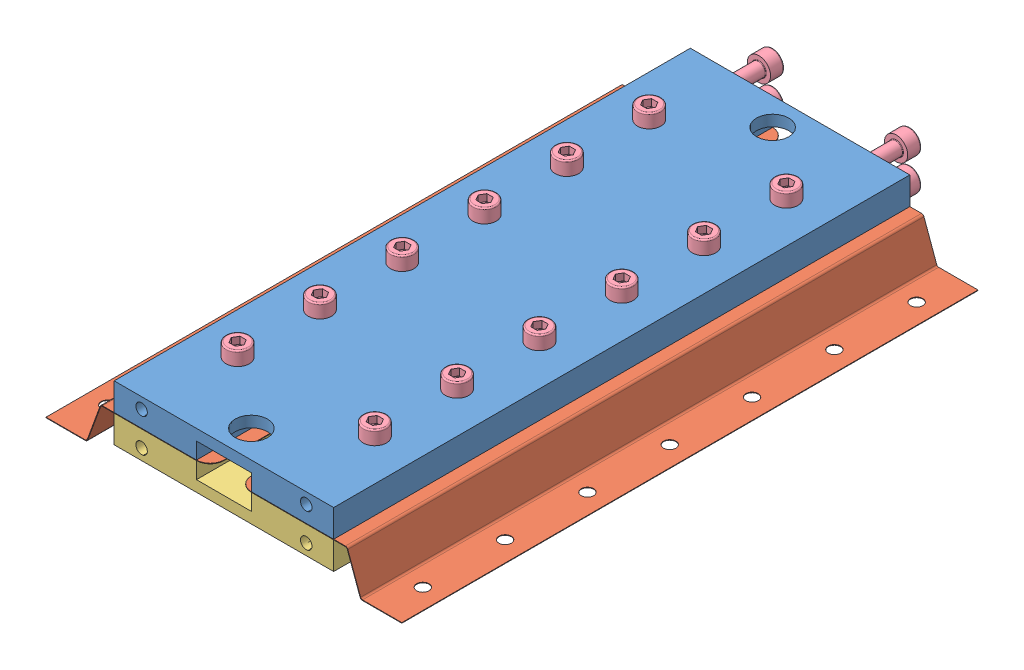
SolidWorks assembly Lasercavity, configuration Standard. Lengths in mm.
Overall size (129.69 29.1 225).
20 component instances, 4 part files, 30 mates.
Components (placement in the parent):
- Cavity top-2: Cavity top [Standard] at (-8.7841 13.8984 210) x (-1 0 0) z (0 0 1) size (80 10 210)
- Electrode-1: Electrode [Standard] at (-3.7841 3.8984 315) x (1 0 0) z (0 1 0) size (59.84 210 14.1)
- Electrode-2: Electrode [Standard] at (-13.7841 3.8984 105) x (-1 0 0) z (0 1 0) size (59.84 210 14.1)
- Cavity Bottom-2: Cavity Bottom [Standard] at (-8.7841 -6.3016 210) size (80 10 210)
- socket head cap screw_din-1: socket head cap screw_din [DIN 912 M5 x 20 --- 20N] at (-33.7841 18.8984 285) x (0 -1 0) z (0 0 1) size (25 8.5 8.5)
- socket head cap screw_din-2: socket head cap screw_din [DIN 912 M5 x 20 --- 20N] at (-33.7841 18.8984 255) x (0 -1 0) z (0 0 1) size (25 8.5 8.5)
- socket head cap screw_din-3: socket head cap screw_din [DIN 912 M5 x 20 --- 20N] at (-33.7841 18.8984 225) x (0 -1 0) z (0 0 1) size (25 8.5 8.5)
- socket head cap screw_din-4: socket head cap screw_din [DIN 912 M5 x 20 --- 20N] at (-33.7841 18.8984 195) x (0 -1 0) z (0 0 1) size (25 8.5 8.5)
- socket head cap screw_din-5: socket head cap screw_din [DIN 912 M5 x 20 --- 20N] at (-33.7841 18.8984 165) x (0 -1 0) z (0 0 1) size (25 8.5 8.5)
- socket head cap screw_din-6: socket head cap screw_din [DIN 912 M5 x 20 --- 20N] at (-33.7841 18.8984 135) x (0 -1 0) z (0 0 1) size (25 8.5 8.5)
- socket head cap screw_din-7: socket head cap screw_din [DIN 912 M5 x 20 --- 20N] at (16.2159 18.8984 135) x (0 -1 0) z (0 0 1) size (25 8.5 8.5)
- socket head cap screw_din-8: socket head cap screw_din [DIN 912 M5 x 20 --- 20N] at (16.2159 18.8984 165) x (0 -1 0) z (0 0 1) size (25 8.5 8.5)
- socket head cap screw_din-9: socket head cap screw_din [DIN 912 M5 x 20 --- 20N] at (16.2159 18.8984 195) x (0 -1 0) z (0 0 1) size (25 8.5 8.5)
- socket head cap screw_din-10: socket head cap screw_din [DIN 912 M5 x 20 --- 20N] at (16.2159 18.8984 225) x (0 -1 0) z (0 0 1) size (25 8.5 8.5)
- socket head cap screw_din-11: socket head cap screw_din [DIN 912 M5 x 20 --- 20N] at (16.2159 18.8984 255) x (0 -1 0) z (0 0 1) size (25 8.5 8.5)
- socket head cap screw_din-12: socket head cap screw_din [DIN 912 M5 x 20 --- 20N] at (16.2159 18.8984 285) x (0 -1 0) z (0 0 1) size (25 8.5 8.5)
- socket head cap screw_din-17: socket head cap screw_din [DIN 912 M5 x 20 --- 20N] at (16.2159 9.7984 90) x (0 0 1) z (-1 0 0) size (25 8.5 8.5)
- socket head cap screw_din-18: socket head cap screw_din [DIN 912 M5 x 20 --- 20N] at (16.2159 -2.2016 90) x (0 0 1) z (-1 0 0) size (25 8.5 8.5)
- socket head cap screw_din-19: socket head cap screw_din [DIN 912 M5 x 20 --- 20N] at (-33.7841 9.7984 90) x (0 0 1) z (-1 0 0) size (25 8.5 8.5)
- socket head cap screw_din-20: socket head cap screw_din [DIN 912 M5 x 20 --- 20N] at (-33.7841 -2.2016 90) x (0 0 1) z (-1 0 0) size (25 8.5 8.5)
Mates (geometry in assembly coordinates):
- Deckungsgleich8: coincident anti-aligned: plane of Gehäuse-2 through (1.2159 3.8984 315) normal (0 -1 0); plane of Elektrode-1 through (-3.7841 3.8984 315) normal (0 1 0)
- Deckungsgleich9: coincident anti-aligned: plane of Gehäuse-2 through (-48.7841 3.8984 315) normal (0 -1 0); plane of Electrode-2 through (-13.7841 3.8984 105) normal (0 1 0)
- Abstand2: distance = 10 mm anti-aligned: plane of Electrode-2 through (-13.7841 3.6984 105) normal (1 0 0); plane of Elektrode-1 through (-3.7841 3.6984 315) normal (-1 0 0)
- Deckungsgleich17: coincident anti-aligned: plane of Electrode-2 through (-13.7841 3.6984 105) normal (0 -1 0); plane of Gehäuse unten-2 through (-18.7841 3.6984 315) normal (0 1 0)
- Deckungsgleich18: coincident aligned: plane of Gehäuse-2 through (-48.7841 13.8984 315) normal (-1 0 0); plane of Gehäuse unten-2 through (-48.7841 3.6984 315) normal (-1 0 0)
- Deckungsgleich19: coincident aligned: plane of Gehäuse-2 through (-8.7841 13.8984 315) normal (0 0 1); plane of Gehäuse unten-2 through (-8.7841 -6.3016 315) normal (0 0 1)
- Konzentrisch1: concentric anti-aligned: cylinder of Gehäuse-2 through (-33.7841 13.8984 285) axis (0 -1 0) radius 2.55; cylinder of socket head cap screw_din-1 through (-33.7841 50.6484 285) axis (0 1 0) radius 4.25
- Deckungsgleich23: coincident anti-aligned: plane of Gehäuse-2 through (31.2159 13.8984 315) normal (0 1 0); plane of socket head cap screw_din-1 through (-29.5341 13.8984 285) normal (0 -1 0)
- Konzentrisch2: concentric anti-aligned: cylinder of Gehäuse-2 through (-33.7841 13.8984 255) axis (0 -1 0) radius 2.55; cylinder of socket head cap screw_din-2 through (-33.7841 50.6484 255) axis (0 1 0) radius 4.25
- Deckungsgleich24: coincident anti-aligned: plane of Gehäuse-2 through (31.2159 13.8984 315) normal (0 1 0); plane of socket head cap screw_din-2 through (-29.5341 13.8984 255) normal (0 -1 0)
- Konzentrisch3: concentric anti-aligned: cylinder of Gehäuse-2 through (-33.7841 13.8984 225) axis (0 -1 0) radius 2.55; cylinder of socket head cap screw_din-3 through (-33.7841 50.6484 225) axis (0 1 0) radius 4.25
- Deckungsgleich25: coincident anti-aligned: plane of Gehäuse-2 through (31.2159 13.8984 315) normal (0 1 0); plane of socket head cap screw_din-3 through (-29.5341 13.8984 225) normal (0 -1 0)
- Konzentrisch4: concentric anti-aligned: cylinder of Gehäuse-2 through (-33.7841 13.8984 195) axis (0 -1 0) radius 2.55; cylinder of socket head cap screw_din-4 through (-33.7841 50.6484 195) axis (0 1 0) radius 4.25
- Deckungsgleich26: coincident anti-aligned: plane of Gehäuse-2 through (31.2159 13.8984 315) normal (0 1 0); plane of socket head cap screw_din-4 through (-29.5341 13.8984 195) normal (0 -1 0)
- Konzentrisch5: concentric anti-aligned: cylinder of Gehäuse-2 through (-33.7841 13.8984 165) axis (0 -1 0) radius 2.55; cylinder of socket head cap screw_din-5 through (-33.7841 50.6484 165) axis (0 1 0) radius 4.25
- Deckungsgleich27: coincident anti-aligned: plane of Gehäuse-2 through (31.2159 13.8984 315) normal (0 1 0); plane of socket head cap screw_din-5 through (-29.5341 13.8984 165) normal (0 -1 0)
- Konzentrisch6: concentric anti-aligned: cylinder of Gehäuse-2 through (-33.7841 13.8984 135) axis (0 -1 0) radius 2.55; cylinder of socket head cap screw_din-6 through (-33.7841 50.6484 135) axis (0 1 0) radius 4.25
- Deckungsgleich28: coincident anti-aligned: plane of Gehäuse-2 through (31.2159 13.8984 315) normal (0 1 0); plane of socket head cap screw_din-6 through (-29.5341 13.8984 135) normal (0 -1 0)
- Konzentrisch7: concentric anti-aligned: cylinder of Gehäuse-2 through (16.2159 13.8984 135) axis (0 -1 0) radius 2.55; cylinder of socket head cap screw_din-7 through (16.2159 50.6484 135) axis (0 1 0) radius 4.25
- Deckungsgleich29: coincident anti-aligned: plane of Gehäuse-2 through (31.2159 13.8984 315) normal (0 1 0); plane of socket head cap screw_din-7 through (20.4659 13.8984 135) normal (0 -1 0)
- Konzentrisch8: concentric anti-aligned: cylinder of Gehäuse-2 through (16.2159 13.8984 165) axis (0 -1 0) radius 2.55; cylinder of socket head cap screw_din-8 through (16.2159 50.6484 165) axis (0 1 0) radius 4.25
- Deckungsgleich30: coincident anti-aligned: plane of Gehäuse-2 through (31.2159 13.8984 315) normal (0 1 0); plane of socket head cap screw_din-8 through (20.4659 13.8984 165) normal (0 -1 0)
- Konzentrisch9: concentric anti-aligned: cylinder of Gehäuse-2 through (16.2159 13.8984 195) axis (0 -1 0) radius 2.55; cylinder of socket head cap screw_din-9 through (16.2159 50.6484 195) axis (0 1 0) radius 4.25
- Deckungsgleich31: coincident anti-aligned: plane of Gehäuse-2 through (31.2159 13.8984 315) normal (0 1 0); plane of socket head cap screw_din-9 through (20.4659 13.8984 195) normal (0 -1 0)
- Konzentrisch10: concentric anti-aligned: cylinder of Gehäuse-2 through (16.2159 13.8984 225) axis (0 -1 0) radius 2.55; cylinder of socket head cap screw_din-10 through (16.2159 50.6484 225) axis (0 1 0) radius 4.25
- Deckungsgleich32: coincident anti-aligned: plane of Gehäuse-2 through (31.2159 13.8984 315) normal (0 1 0); plane of socket head cap screw_din-10 through (20.4659 13.8984 225) normal (0 -1 0)
- Konzentrisch11: concentric anti-aligned: cylinder of Gehäuse-2 through (16.2159 13.8984 255) axis (0 -1 0) radius 2.55; cylinder of socket head cap screw_din-11 through (16.2159 50.6484 255) axis (0 1 0) radius 4.25
- Deckungsgleich33: coincident anti-aligned: plane of Gehäuse-2 through (31.2159 13.8984 315) normal (0 1 0); plane of socket head cap screw_din-11 through (20.4659 13.8984 255) normal (0 -1 0)
- Konzentrisch12: concentric anti-aligned: cylinder of Gehäuse-2 through (16.2159 13.8984 285) axis (0 -1 0) radius 2.55; cylinder of socket head cap screw_din-12 through (16.2159 50.6484 285) axis (0 1 0) radius 4.25
- Deckungsgleich34: coincident anti-aligned: plane of Gehäuse-2 through (31.2159 13.8984 315) normal (0 1 0); plane of socket head cap screw_din-12 through (20.4659 13.8984 285) normal (0 -1 0)
